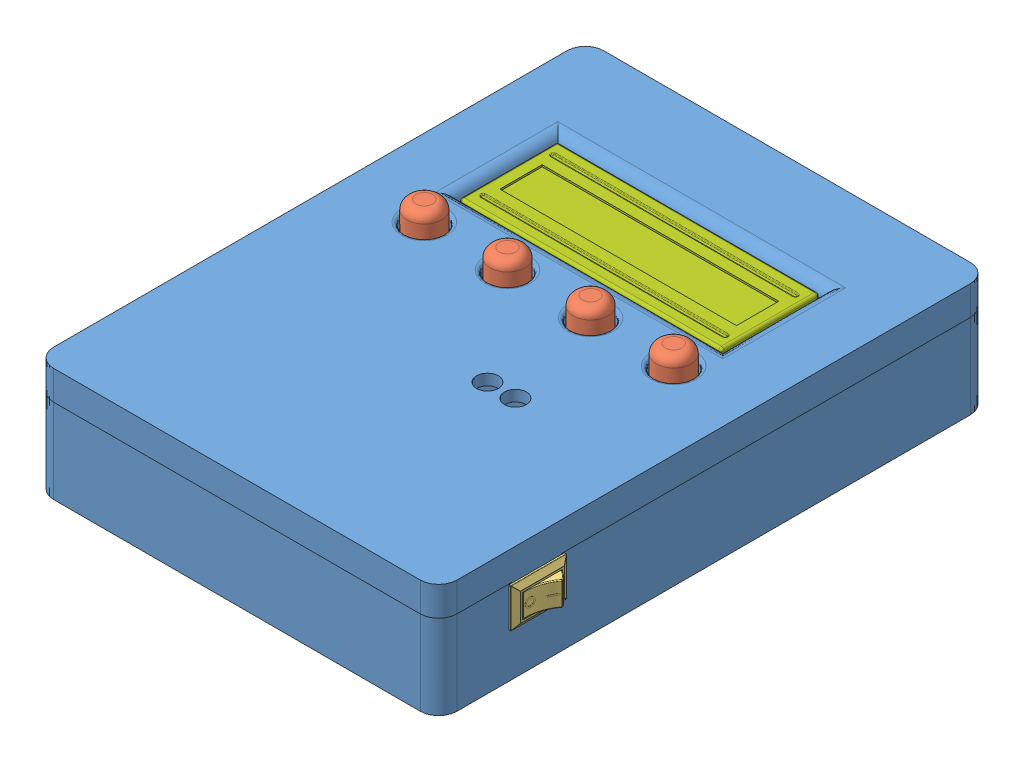
SolidWorks assembly Montagem, configuration Valor predeterminado. Lengths in mm.
Overall size (114.08 36.77 150).
187 component instances, 39 part files, 37 mates.
Components (placement in the parent):
- B01-2: B01 [Valor predeterminado] at (-46.8691 -11.7916 150) size (110 23 150)
- PCB_V02-2: PCB_V02 [Valor predeterminado] at (-92.8691 -3.7916 178) x (1 0 0) z (0 1 0) size (93.53 97.66 25.25)
  - Gerador Senhas.stp-1: Gerador Senhas.stp [Valor predeterminado] at origin size (93.53 97.66 25.7)
    - PCB Component.stp-1: PCB Component.stp [Valor predeterminado] at origin size (93.53 97.66 25.7)
      - ARDUINO-NANO.stp-1: ARDUINO-NANO.stp [Valor predeterminado] at (39.37 21.59 1.57) x (0 -1 0) z (0 0 1) size (17.9 45.1 23.75)
        - PCB.stp-1: PCB.stp [Valor predeterminado] at (-1.2568 4.2028 12.5) x (0 -1 0) z (1 0 0) size (45.1 18 17.9)
          - TopFace.stp-1: TopFace.stp [Valor predeterminado] at origin size (45.1 11.25 12.1)
            - Leds.stp-1: Leds.stp [Valor predeterminado] at origin size (4.2 0.5 12.1)
              - Led.stp-1: Led.stp [Valor predeterminado] at (3.25 0 -13.6) size (4.2 0.5 1.3)
              - Led.stp-2: Led.stp [Valor predeterminado] at (3.25 0 -17.2) size (4.2 0.5 1.3)
              - Led.stp-3: Led.stp [Valor predeterminado] at (3.25 0 -20.8) size (4.2 0.5 1.3)
              - Led (1).stp-1: Led (1).stp [Valor predeterminado] at (3.25 0 -10) size (4.2 0.5 1.3)
            - PinEnd.stp-1: PinEnd.stp [Valor predeterminado] at (0 0 -2.54) size (5.08 11.25 7.62)
              - Pin.stp-1: Pin.stp [Valor predeterminado] at (25 1.6 57.68) x (1 0 0) z (0 0 -1) size (2.54 11.25 2.54)
              - Pin.stp-2: Pin.stp [Valor predeterminado] at (25 1.6 60.22) x (1 0 0) z (0 0 -1) size (2.54 11.25 2.54)
              - Pin.stp-3: Pin.stp [Valor predeterminado] at (25 1.6 62.76) x (1 0 0) z (0 0 -1) size (2.54 11.25 2.54)
              - Pin.stp-4: Pin.stp [Valor predeterminado] at (27.54 1.6 57.68) x (1 0 0) z (0 0 -1) size (2.54 11.25 2.54)
              - Pin.stp-5: Pin.stp [Valor predeterminado] at (27.54 1.6 60.22) x (1 0 0) z (0 0 -1) size (2.54 11.25 2.54)
              - Pin.stp-6: Pin.stp [Valor predeterminado] at (27.54 1.6 62.76) x (1 0 0) z (0 0 -1) size (2.54 11.25 2.54)
            - switch.stp-1: switch.stp [Valor predeterminado] at (1.3966 -1.5 22.3391) size (3 1.7 4.8)
            - chip1.stp-1: chip1.stp [Valor predeterminado] at origin size (11.76 1.3 11.76)
            - USB.stp-1: USB.stp [Valor predeterminado] at origin size (10.18 3.8 11.01)
            - Crystal.stp-1: Crystal.stp [Valor predeterminado] at origin size (2.71 1.1 2.71)
          - BottomFace.stp-1: BottomFace.stp [Valor predeterminado] at origin size (40.75 11.25 17.9)
            - PinRow2.stp-1: PinRow2.stp [Valor predeterminado] at (0 0 17.9) size (38.1 11.25 2.54)
              - Pin (1).stp-1: Pin (1).stp [Valor predeterminado] at (45.58 0 32.1) size (2.54 11.25 2.54)
              - Pin (1).stp-2: Pin (1).stp [Valor predeterminado] at (48.12 0 32.1) size (2.54 11.25 2.54)
              - Pin (1).stp-3: Pin (1).stp [Valor predeterminado] at (50.66 0 32.1) size (2.54 11.25 2.54)
              - Pin (1).stp-4: Pin (1).stp [Valor predeterminado] at (53.2 0 32.1) size (2.54 11.25 2.54)
              - Pin (1).stp-5: Pin (1).stp [Valor predeterminado] at (55.74 0 32.1) size (2.54 11.25 2.54)
              - Pin (1).stp-6: Pin (1).stp [Valor predeterminado] at (58.28 0 32.1) size (2.54 11.25 2.54)
              - Pin (1).stp-7: Pin (1).stp [Valor predeterminado] at (60.82 0 32.1) size (2.54 11.25 2.54)
              - Pin (1).stp-8: Pin (1).stp [Valor predeterminado] at (63.36 0 32.1) size (2.54 11.25 2.54)
              - Pin (1).stp-9: Pin (1).stp [Valor predeterminado] at (43.04 0 32.1) size (2.54 11.25 2.54)
              - Pin (1).stp-10: Pin (1).stp [Valor predeterminado] at (40.5 0 32.1) size (2.54 11.25 2.54)
              - Pin (1).stp-11: Pin (1).stp [Valor predeterminado] at (37.96 0 32.1) size (2.54 11.25 2.54)
              - Pin (1).stp-12: Pin (1).stp [Valor predeterminado] at (35.42 0 32.1) size (2.54 11.25 2.54)
              - Pin (1).stp-13: Pin (1).stp [Valor predeterminado] at (32.88 0 32.1) size (2.54 11.25 2.54)
              - Pin (1).stp-14: Pin (1).stp [Valor predeterminado] at (30.34 0 32.1) size (2.54 11.25 2.54)
              - Pin (1).stp-15: Pin (1).stp [Valor predeterminado] at (27.8 0 32.1) size (2.54 11.25 2.54)
            - PinRow1.stp-1: PinRow1.stp [Valor predeterminado] at origin size (38.1 11.25 2.54)
              - Pin.stp-1: Pin.stp [Valor predeterminado] at (45.58 0 -32.1) size (2.54 11.25 2.54)
              - Pin.stp-2: Pin.stp [Valor predeterminado] at (48.12 0 -32.1) size (2.54 11.25 2.54)
              - Pin.stp-3: Pin.stp [Valor predeterminado] at (50.66 0 -32.1) size (2.54 11.25 2.54)
              - Pin.stp-4: Pin.stp [Valor predeterminado] at (53.2 0 -32.1) size (2.54 11.25 2.54)
              - Pin.stp-5: Pin.stp [Valor predeterminado] at (55.74 0 -32.1) size (2.54 11.25 2.54)
              - Pin.stp-6: Pin.stp [Valor predeterminado] at (58.28 0 -32.1) size (2.54 11.25 2.54)
              - Pin.stp-7: Pin.stp [Valor predeterminado] at (60.82 0 -32.1) size (2.54 11.25 2.54)
              - Pin.stp-8: Pin.stp [Valor predeterminado] at (63.36 0 -32.1) size (2.54 11.25 2.54)
              - Pin.stp-9: Pin.stp [Valor predeterminado] at (43.04 0 -32.1) size (2.54 11.25 2.54)
              - Pin.stp-10: Pin.stp [Valor predeterminado] at (40.5 0 -32.1) size (2.54 11.25 2.54)
              - Pin.stp-11: Pin.stp [Valor predeterminado] at (37.96 0 -32.1) size (2.54 11.25 2.54)
              - Pin.stp-12: Pin.stp [Valor predeterminado] at (35.42 0 -32.1) size (2.54 11.25 2.54)
              - Pin.stp-13: Pin.stp [Valor predeterminado] at (32.88 0 -32.1) size (2.54 11.25 2.54)
              - Pin.stp-14: Pin.stp [Valor predeterminado] at (30.34 0 -32.1) size (2.54 11.25 2.54)
              - Pin.stp-15: Pin.stp [Valor predeterminado] at (27.8 0 -32.1) size (2.54 11.25 2.54)
            - Resistors.stp-1: Resistors.stp [Valor predeterminado] at origin size (32.5 1 11.3)
              - Res.stp-1: Res.stp [Valor predeterminado] at (12.2 1.6 29.15) x (0 0 -1) z (1 0 0) size (1.3 1 4)
              - Res.stp-2: Res.stp [Valor predeterminado] at (12.2 1.6 24.6) x (0 0 -1) z (1 0 0) size (1.3 1 4)
              - Res.stp-3: Res.stp [Valor predeterminado] at (-2.9 1.6 23.1) x (0 0 -1) z (1 0 0) size (1.3 1 4)
              - Res.stp-4: Res.stp [Valor predeterminado] at (-2.9 1.6 26.2) x (0 0 -1) z (1 0 0) size (1.3 1 4)
              - Res.stp-5: Res.stp [Valor predeterminado] at (-16.3 1.6 19.15) x (0 0 -1) z (1 0 0) size (1.3 1 4)
            - caps.stp-1: caps.stp [Valor predeterminado] at origin size (33.2 1.51 4.35)
              - cap.stp-1: cap.stp [Valor predeterminado] at (68.25 1.6 43.825) x (-1 0 0) z (0 0 -1) size (3.7 1.51 1.65)
              - cap.stp-2: cap.stp [Valor predeterminado] at (-14.35 1.6 -32.125) size (3.7 1.51 1.65)
            - respacks.stp-1: respacks.stp [Valor predeterminado] at origin size (3.22 0.9 8.4)
              - respack.stp-1: respack.stp [Valor predeterminado] at (-0.85 1.6 -21.8) size (3.22 0.9 3.4)
              - respack.stp-2: respack.stp [Valor predeterminado] at (-0.85 1.6 -26.8) size (3.22 0.9 3.4)
            - Chip.stp-1: Chip.stp [Valor predeterminado] at origin size (10 1.5 8.03)
            - diode.stp-1: diode.stp [Valor predeterminado] at (0.15 1.6 -28.35) size (1.6 1 4.3)
            - vreg.stp-1: vreg.stp [Valor predeterminado] at (-16.3 1.6 -15.5) size (8.5 1.6 6)
          - PCB-0.stp-1: PCB-0.stp [Valor predeterminado] at origin size (43.7 1.6 17.9)
        - Headers.stp-1: Headers.stp [Valor predeterminado] at (-1.2568 4.2028 12.5) x (0 -1 0) z (1 0 0) size (38.1 11.45 17.78)
          - Header Female 15 v1.stp-1: Header Female 15 v1.stp [Valor predeterminado] at (4.07 12.55 16.51) x (1 0 0) z (0 -1 0) size (38.1 2.54 11.45)
            - HF1.stp-1: HF1.stp [Valor predeterminado] at origin size (2.54 2.54 11.45)
            - HF1.stp-2: HF1.stp [Valor predeterminado] at (2.54 0 0) size (2.54 2.54 11.45)
            - HF1.stp-3: HF1.stp [Valor predeterminado] at (5.08 0 0) size (2.54 2.54 11.45)
            - HF1.stp-4: HF1.stp [Valor predeterminado] at (7.62 0 0) size (2.54 2.54 11.45)
            - HF1.stp-5: HF1.stp [Valor predeterminado] at (10.16 0 0) size (2.54 2.54 11.45)
            - HF1.stp-6: HF1.stp [Valor predeterminado] at (12.7 0 0) size (2.54 2.54 11.45)
            - HF1.stp-7: HF1.stp [Valor predeterminado] at (15.24 0 0) size (2.54 2.54 11.45)
            - HF1.stp-8: HF1.stp [Valor predeterminado] at (17.78 0 0) size (2.54 2.54 11.45)
            - HF1.stp-9: HF1.stp [Valor predeterminado] at (20.32 0 0) size (2.54 2.54 11.45)
            - HF1.stp-10: HF1.stp [Valor predeterminado] at (22.86 0 0) size (2.54 2.54 11.45)
            - HF1.stp-11: HF1.stp [Valor predeterminado] at (25.4 0 0) size (2.54 2.54 11.45)
            - HF1.stp-12: HF1.stp [Valor predeterminado] at (27.94 0 0) size (2.54 2.54 11.45)
            - HF1.stp-13: HF1.stp [Valor predeterminado] at (30.48 0 0) size (2.54 2.54 11.45)
            - HF1.stp-14: HF1.stp [Valor predeterminado] at (33.02 0 0) size (2.54 2.54 11.45)
            - HF1.stp-15: HF1.stp [Valor predeterminado] at (35.56 0 0) size (2.54 2.54 11.45)
          - Header Female 15 v1 (1).stp-1: Header Female 15 v1 (1).stp [Valor predeterminado] at (4.07 12.55 1.27) x (1 0 0) z (0 -1 0) size (38.1 2.54 11.45)
            - HF1.stp-1: HF1.stp [Valor predeterminado] at origin size (2.54 2.54 11.45)
            - HF1.stp-2: HF1.stp [Valor predeterminado] at (2.54 0 0) size (2.54 2.54 11.45)
            - HF1.stp-3: HF1.stp [Valor predeterminado] at (5.08 0 0) size (2.54 2.54 11.45)
            - HF1.stp-4: HF1.stp [Valor predeterminado] at (7.62 0 0) size (2.54 2.54 11.45)
            - HF1.stp-5: HF1.stp [Valor predeterminado] at (10.16 0 0) size (2.54 2.54 11.45)
            - HF1.stp-6: HF1.stp [Valor predeterminado] at (12.7 0 0) size (2.54 2.54 11.45)
            - HF1.stp-7: HF1.stp [Valor predeterminado] at (15.24 0 0) size (2.54 2.54 11.45)
            - HF1.stp-8: HF1.stp [Valor predeterminado] at (17.78 0 0) size (2.54 2.54 11.45)
            - HF1.stp-9: HF1.stp [Valor predeterminado] at (20.32 0 0) size (2.54 2.54 11.45)
            - HF1.stp-10: HF1.stp [Valor predeterminado] at (22.86 0 0) size (2.54 2.54 11.45)
            - HF1.stp-11: HF1.stp [Valor predeterminado] at (25.4 0 0) size (2.54 2.54 11.45)
            - HF1.stp-12: HF1.stp [Valor predeterminado] at (27.94 0 0) size (2.54 2.54 11.45)
            - HF1.stp-13: HF1.stp [Valor predeterminado] at (30.48 0 0) size (2.54 2.54 11.45)
            - HF1.stp-14: HF1.stp [Valor predeterminado] at (33.02 0 0) size (2.54 2.54 11.45)
            - HF1.stp-15: HF1.stp [Valor predeterminado] at (35.56 0 0) size (2.54 2.54 11.45)
      - PUSHBUTTON.stp-1: PUSHBUTTON.stp [Valor predeterminado] at (12 38.1 1.57) size (7.7 6 7.8)
        - B3F_1000_BUTTON.stp-1: B3F_1000_BUTTON.stp [Valor predeterminado] at (0 0 4.3) x (-1 0 0) z (0 1 0) size (3.5 1 3.5)
        - B3F_1000_BASE.stp-1: B3F_1000_BASE.stp [Valor predeterminado] x (1 0 0) z (0 -1 0) size (7.7 7.4 6)
      - PUSHBUTTON.stp-2: PUSHBUTTON.stp [Valor predeterminado] at (34.667 38.1 1.57) size (7.7 6 7.8)
        - B3F_1000_BUTTON.stp-1: B3F_1000_BUTTON.stp [Valor predeterminado] at (0 0 4.3) x (-1 0 0) z (0 1 0) size (3.5 1 3.5)
        - B3F_1000_BASE.stp-1: B3F_1000_BASE.stp [Valor predeterminado] x (1 0 0) z (0 -1 0) size (7.7 7.4 6)
      - PUSHBUTTON.stp-3: PUSHBUTTON.stp [Valor predeterminado] at (57.333 38.1 1.57) size (7.7 6 7.8)
        - B3F_1000_BUTTON.stp-1: B3F_1000_BUTTON.stp [Valor predeterminado] at (0 0 4.3) x (-1 0 0) z (0 1 0) size (3.5 1 3.5)
        - B3F_1000_BASE.stp-1: B3F_1000_BASE.stp [Valor predeterminado] x (1 0 0) z (0 -1 0) size (7.7 7.4 6)
      - PUSHBUTTON.stp-4: PUSHBUTTON.stp [Valor predeterminado] at (80 38.1 1.57) size (7.7 6 7.8)
        - B3F_1000_BUTTON.stp-1: B3F_1000_BUTTON.stp [Valor predeterminado] at (0 0 4.3) x (-1 0 0) z (0 1 0) size (3.5 1 3.5)
        - B3F_1000_BASE.stp-1: B3F_1000_BASE.stp [Valor predeterminado] x (1 0 0) z (0 -1 0) size (7.7 7.4 6)
      - 1N4004.stp-1: 1N4004.stp [Valor predeterminado] at (73.66 2.54 1.57) size (10.38 2.7 5.35)
        - User Library-DO-41_375mil_Fillet001.stp-1: User Library-DO-41_375mil_Fillet001.stp [Valor predeterminado] at (4.7457 0.3612 0) x (-1 0 0) z (0 0 1) size (3.72 2.7 2.7)
        - User Library-DO-41_375mil_Fillet.stp-1: User Library-DO-41_375mil_Fillet.stp [Valor predeterminado] at (4.7457 0.3612 0) x (-1 0 0) z (0 0 1) size (1 2.7 2.7)
        - User Library-DO-41_375mil_DO_41_375mil001.stp-1: User Library-DO-41_375mil_DO_41_375mil001.stp [Valor predeterminado] at (4.7457 0.3612 0) x (-1 0 0) z (0 0 1) size (2.55 0.86 4.43)
        - User Library-DO-41_375mil_DO_41_375mil.stp-1: User Library-DO-41_375mil_DO_41_375mil.stp [Valor predeterminado] at (4.7457 0.3612 0) x (-1 0 0) z (0 0 1) size (2.55 0.86 4.43)
        - User Library-DO-41_375mil_DO_41_375mil003.stp-1: User Library-DO-41_375mil_DO_41_375mil003.stp [Valor predeterminado] at (4.7457 0.3612 0) x (-1 0 0) z (0 0 1) size (1 2.7 2.7)
      - LCD-16X2-V2.stp-1: LCD-16X2-V2.stp [Valor predeterminado] at (46 64.77 1.57) size (80.7 36 23.25)
        - DISPLAY-LCD.stp-1: DISPLAY-LCD.stp [Valor predeterminado] at (-0.3985 0.0488 8.5541) size (80.7 36 16.8)
        - Header Female 15 v1 (2).stp-1: Header Female 15 v1 (2).stp [Valor predeterminado] at (-29.5885 15.5718 0.0005) size (38.1 2.54 11.45)
        - Header Female 15 v1 - Copia.stp-1: Header Female 15 v1 - Copia.stp [Valor predeterminado] at (-32.1285 15.5718 0.0005) size (2.54 2.54 11.45)
      - Board.stp-1: Board.stp [Valor predeterminado] at origin size (92 94 1.57)
      - 10k.stp-1: 10k.stp [Valor predeterminado] at (57.15 21.59 1.57) x (0 1 0) z (0 0 1) size (8.2 1.6 3.52)
      - 10k.stp-2: 10k.stp [Valor predeterminado] at (64.77 21.59 1.57) x (0 1 0) z (0 0 1) size (8.2 1.6 3.52)
      - 10k.stp-3: 10k.stp [Valor predeterminado] at (15.24 43.18 1.57) size (8.2 1.6 3.52)
      - 10k.stp-4: 10k.stp [Valor predeterminado] at (38.1 43.18 1.57) size (8.2 1.6 3.52)
      - 10k.stp-5: 10k.stp [Valor predeterminado] at (60.96 43.18 1.57) size (8.2 1.6 3.52)
      - 10k.stp-6: 10k.stp [Valor predeterminado] at (83.82 43.18 1.57) size (8.2 1.6 3.52)
      - 1X02_90.stp-1: 1X02_90.stp [Valor predeterminado] at (83.82 2.54 1.57) x (-1 0 0) z (0 0 1) size (5.08 10.36 5.54)
      - LED5MM.stp-1: LED5MM.stp [Valor predeterminado] at (58.42 8.89 1.57) size (5.1 5.1 13.6)
      - LED5MM.stp-2: LED5MM.stp [Valor predeterminado] at (66.04 8.89 1.57) size (5.1 5.1 13.6)
  - pan head cross recess screw_iso-1: pan head cross recess screw_iso [ISO 7045 - M2 x 20 - Z - 20N] at (83.5 80.27 -1.6) x (0 0 1) z (-1 0 0) size (21.57 4 4)
  - pan head cross recess screw_iso-2: pan head cross recess screw_iso [ISO 7045 - M2 x 20 - Z - 20N] at (83.5 49.27 -1.6) x (0 0 1) z (-1 0 0) size (21.57 4 4)
  - pan head cross recess screw_iso-3: pan head cross recess screw_iso [ISO 7045 - M2 x 20 - Z - 20N] at (8.5 49.27 -1.6) x (0 0 1) z (-1 0 0) size (21.57 4 4)
  - pan head cross recess screw_iso-4: pan head cross recess screw_iso [ISO 7045 - M2 x 20 - Z - 20N] at (8.5 80.27 -1.6) x (0 0 1) z (-1 0 0) size (21.57 4 4)
  - plain washer 10673 type snl_iso-1: plain washer 10673 type snl_iso [ISO 10673-2.25-S] at (83.5 80.27 1.57) x (0 0 1) z (-1 0 0) size (0.6 5 5)
  - plain washer 10673 type snl_iso-2: plain washer 10673 type snl_iso [ISO 10673-2.25-S] at (83.6015 80.6118 14.0205) x (0 0 1) z (-1 0 0) size (0.6 5 5)
  - plain washer 10673 type snl_iso-3: plain washer 10673 type snl_iso [ISO 10673-2.25-S] at (83.6015 80.6118 12.5205) x (0 0 -1) z (1 0 0) size (0.6 5 5)
  - plain washer 10673 type snl_iso-4: plain washer 10673 type snl_iso [ISO 10673-2.25-S] at (83.5 49.27 12.2061) x (0 0 1) z (-1 0 0) size (0.6 5 5)
  - plain washer 10673 type snl_iso-5: plain washer 10673 type snl_iso [ISO 10673-2.25-S] at (83.6015 48.6118 14.0205) x (0 0 1) z (-1 0 0) size (0.6 5 5)
  - plain washer 10673 type snl_iso-6: plain washer 10673 type snl_iso [ISO 10673-2.25-S] at (83.5 49.27 1.57) x (0 0 1) z (-1 0 0) size (0.6 5 5)
  - plain washer 10673 type snl_iso-7: plain washer 10673 type snl_iso [ISO 10673-2.25-S] at (8.5 49.27 1.763) x (0 0 1) z (-1 0 0) size (0.6 5 5)
  - plain washer 10673 type snl_iso-8: plain washer 10673 type snl_iso [ISO 10673-2.25-S] at (7.6015 48.6118 14.0205) x (0 0 1) z (-1 0 0) size (0.6 5 5)
  - plain washer 10673 type snl_iso-9: plain washer 10673 type snl_iso [ISO 10673-2.25-S] at (7.6015 80.6118 14.0205) x (0 0 1) z (-1 0 0) size (0.6 5 5)
  - plain washer 10673 type snl_iso-10: plain washer 10673 type snl_iso [ISO 10673-2.25-S] at (8.5 80.27 1.57) x (0 0 1) z (-1 0 0) size (0.6 5 5)
  - plain washer 10673 type snl_iso-12: plain washer 10673 type snl_iso [ISO 10673-2.25-S] at (7.6015 48.6118 12.5205) x (0 0 -1) z (1 0 0) size (0.6 5 5)
  - plain washer 10673 type snl_iso-13: plain washer 10673 type snl_iso [ISO 10673-2.25-S] at (7.6015 80.6118 12.5205) x (0 0 -1) z (1 0 0) size (0.6 5 5)
  - hex thin nut gradeb_iso-2: hex thin nut gradeb_iso [ISO - 4036 - M1.6 - N] at (83.6015 80.6118 15.6205) size (3.2 3.7 1)
  - hex thin nut gradeb_iso-3: hex thin nut gradeb_iso [ISO - 4036 - M1.6 - N] at (83.5 80.27 3.17) size (3.2 3.7 1)
  - hex thin nut gradeb_iso-4: hex thin nut gradeb_iso [ISO - 4036 - M1.6 - N] at (83.6015 80.6118 10.9205) x (0.923728 0.383049 0) z (0 0 -1) size (3.2 3.7 1)
  - hex thin nut gradeb_iso-5: hex thin nut gradeb_iso [ISO - 4036 - M1.6 - N] at (83.5 49.27 11.2061) x (0.923728 0.383049 0) z (0 0 -1) size (3.2 3.7 1)
  - hex thin nut gradeb_iso-6: hex thin nut gradeb_iso [ISO - 4036 - M1.6 - N] at (83.5 49.27 3.17) size (3.2 3.7 1)
  - hex thin nut gradeb_iso-7: hex thin nut gradeb_iso [ISO - 4036 - M1.6 - N] at (83.6015 48.6118 15.6205) size (3.2 3.7 1)
  - hex thin nut gradeb_iso-8: hex thin nut gradeb_iso [ISO - 4036 - M1.6 - N] at (7.6015 80.6118 15.6205) size (3.2 3.7 1)
  - hex thin nut gradeb_iso-9: hex thin nut gradeb_iso [ISO - 4036 - M1.6 - N] at (7.6015 48.6118 15.6205) size (3.2 3.7 1)
  - hex thin nut gradeb_iso-10: hex thin nut gradeb_iso [ISO - 4036 - M1.6 - N] at (7.6015 48.6118 10.9205) x (0.923728 0.383049 0) z (0 0 -1) size (3.2 3.7 1)
  - hex thin nut gradeb_iso-11: hex thin nut gradeb_iso [ISO - 4036 - M1.6 - N] at (8.5 80.27 10.9205) x (-0.825808 -0.563951 0) z (0 0 -1) size (3.2 3.7 1)
  - hex thin nut gradeb_iso-12: hex thin nut gradeb_iso [ISO - 4036 - M1.6 - N] at (8.5 80.27 3.17) size (3.2 3.7 1)
  - hex thin nut gradeb_iso-13: hex thin nut gradeb_iso [ISO - 4036 - M1.6 - N] at (8.5 49.27 3.363) size (3.2 3.7 1)
- countersunk flat head cross recess screw_iso-1: countersunk flat head cross recess screw_iso [ISO 7046-1 - M3 x 16 - Z - 16N] at (-8.8691 -11.7916 90) x (0 1 0) z (0.016803 0 0.999859) size (16 5.5 5.5)
- countersunk flat head cross recess screw_iso-2: countersunk flat head cross recess screw_iso [ISO 7046-1 - M3 x 16 - Z - 16N] at (-8.8691 -11.7916 163) x (0 1 0) z (0.01222 0 0.999925) size (16 5.5 5.5)
- countersunk flat head cross recess screw_iso-3: countersunk flat head cross recess screw_iso [ISO 7046-1 - M3 x 16 - Z - 16N] at (-84.8691 -11.7916 148) x (0 1 0) z (0 0 1) size (16 5.5 5.5)
- countersunk flat head cross recess screw_iso-4: countersunk flat head cross recess screw_iso [ISO 7046-1 - M3 x 16 - Z - 16N] at (-84.8691 -11.7916 92) x (0 1 0) z (0.018147 0 0.999835) size (16 5.5 5.5)
- plain washer 10673 type snl_iso-1: plain washer 10673 type snl_iso [ISO 10673-3.2-S] at (-8.8691 0.079 90) x (0 1 0) z (0 0 1) size (0.8 7 7)
- plain washer 10673 type snl_iso-2: plain washer 10673 type snl_iso [ISO 10673-3.2-S] at (-8.8691 0.0706 163) x (0 1 0) z (0 0 1) size (0.8 7 7)
- plain washer 10673 type snl_iso-3: plain washer 10673 type snl_iso [ISO 10673-3.2-S] at (-84.8691 -2.2216 148) x (0 1 0) z (0 0 1) size (0.8 7 7)
- plain washer 10673 type snl_iso-4: plain washer 10673 type snl_iso [ISO 10673-3.2-S] at (-84.8691 -2.2216 92) x (0 1 0) z (0 0 1) size (0.8 7 7)
- hex thin nut chamfered gradeab_iso-1: hex thin nut chamfered gradeab_iso [ISO - 4035 - M3 - N] at (-8.8691 2.679 90) x (1 0 0) z (0 1 0) size (5.5 6.35 1.8)
- hex thin nut chamfered gradeab_iso-2: hex thin nut chamfered gradeab_iso [ISO - 4035 - M3 - N] at (-8.8691 2.6706 163) x (1 0 0) z (0 1 0) size (5.5 6.35 1.8)
- hex thin nut chamfered gradeab_iso-3: hex thin nut chamfered gradeab_iso [ISO - 4035 - M3 - N] at (-84.8691 0.3784 148) x (1 0 0) z (0 1 0) size (5.5 6.35 1.8)
- hex thin nut chamfered gradeab_iso-4: hex thin nut chamfered gradeab_iso [ISO - 4035 - M3 - N] at (-84.8691 0.3784 92) x (1 0 0) z (0 1 0) size (5.5 6.35 1.8)
- B02-1: B02 [Valor predeterminado] at (-46.8691 19.2084 150) size (110 9 150)
- BT-1: BT [Valor predeterminado] at (-6.001 2.0784 140.016) x (0.999857 0 0.016893) z (-0.016893 0 0.999857) size (13.5 22.5 13.5)
- BT-2: BT [Valor predeterminado] at (-28.6667 2.0784 139.9) size (13.5 22.5 13.5)
- BT-3: BT [Valor predeterminado] at (-51.3334 2.0784 139.9) size (13.5 22.5 13.5)
- BT-4: BT [Valor predeterminado] at (-74 2.0784 139.9) size (13.5 22.5 13.5)
- countersunk flat head cross recess screw_iso-5: countersunk flat head cross recess screw_iso [ISO 7046-1 - M3 x 25 - Z - 25N] at (-96.8691 -11.7916 80) x (0 1 0) z (0.026158 0 0.999658) size (25 5.5 5.5)
- countersunk flat head cross recess screw_iso-6: countersunk flat head cross recess screw_iso [ISO 7046-1 - M3 x 25 - Z - 25N] at (3.1309 -11.7916 80) x (0 1 0) z (-0.021009 0 0.999779) size (25 5.5 5.5)
- countersunk flat head cross recess screw_iso-7: countersunk flat head cross recess screw_iso [ISO 7046-1 - M3 x 25 - Z - 25N] at (3.1309 -11.7916 220) x (0 1 0) z (0.093067 0 0.99566) size (25 5.5 5.5)
- countersunk flat head cross recess screw_iso-8: countersunk flat head cross recess screw_iso [ISO 7046-1 - M3 x 25 - Z - 25N] at (-96.8691 -12.1916 220) x (0 1 0) z (0 0 1) size (25 5.5 5.5)
- Mini Rocker Switch-1: Mini Rocker Switch [Default] at (8.1309 5.6534 198.25) x (0 -1 0) z (0 0 1) size (10.67 19.51 15.75)
Mates (geometry in assembly coordinates):
- Concêntrico2: concentric anti-aligned: cylinder of B01-2 through (-84.8691 -11.7916 92) axis (0 -1 0) radius 1.7; cylinder of PCB_V02-2/Gerador Senhas.stp-1/PCB Component.stp-1/Board.stp-1 through (-84.8691 -3.7916 92) axis (0 1 0) radius 1.75
- Concêntrico3: concentric anti-aligned: cylinder of B01-2 through (-8.8691 -11.7916 163) axis (0 -1 0) radius 1.7; cylinder of PCB_V02-2/Gerador Senhas.stp-1/PCB Component.stp-1/Board.stp-1 through (-8.8691 -3.7916 163) axis (0 1 0) radius 1.75
- Coincidente1: coincident anti-aligned: circle of B01-2; plane of PCB_V02-2/Gerador Senhas.stp-1/PCB Component.stp-1/Board.stp-1 through (-46.8691 -3.7916 131) normal (0 -1 0)
- Coincidente2: coincident aligned: cone of B01-2 through (-8.8691 -11.7916 90) axis (0 1 0); cone of countersunk flat head cross recess screw_iso-1 through (-8.8691 -11.3916 90) axis (0 1 0)
- Coincidente3: coincident aligned: cone of B01-2 through (-8.8691 -11.7916 163) axis (0 1 0); cone of countersunk flat head cross recess screw_iso-2 through (-8.8691 -11.3916 163) axis (0 1 0)
- Coincidente5: coincident aligned: cone of B01-2 through (-84.8691 -11.7916 92) axis (0 1 0); cone of countersunk flat head cross recess screw_iso-4 through (-84.8691 -11.3916 92) axis (0 1 0)
- Concêntrico4: concentric aligned: cylinder of countersunk flat head cross recess screw_iso-1 through (-8.8691 -18.1416 90) axis (0 -1 0) radius 1.5; cylinder of plain washer 10673 type snl_iso-1 through (-8.8691 0.879 90) axis (0 -1 0) radius 1.6
- Concêntrico5: concentric aligned: cylinder of countersunk flat head cross recess screw_iso-2 through (-8.8691 -18.1416 163) axis (0 -1 0) radius 1.5; cylinder of plain washer 10673 type snl_iso-2 through (-8.8691 0.8706 163) axis (0 -1 0) radius 1.6
- Concêntrico6: concentric anti-aligned: cylinder of PCB_V02-2/Gerador Senhas.stp-1/PCB Component.stp-1/Board.stp-1 through (-84.8691 -3.7916 148) axis (0 1 0) radius 1.75; cylinder of plain washer 10673 type snl_iso-3 through (-84.8691 -1.4216 148) axis (0 -1 0) radius 1.6
- Coincidente6: coincident anti-aligned: plane of PCB_V02-2/Gerador Senhas.stp-1/PCB Component.stp-1/Board.stp-1 through (-46.8691 -2.2216 131) normal (0 1 0); plane of plain washer 10673 type snl_iso-3 through (-84.8691 -2.2216 148) normal (0 -1 0)
- Concêntrico7: concentric anti-aligned: cylinder of PCB_V02-2/Gerador Senhas.stp-1/PCB Component.stp-1/Board.stp-1 through (-84.8691 -3.7916 92) axis (0 1 0) radius 1.75; cylinder of plain washer 10673 type snl_iso-4 through (-84.8691 -1.4216 92) axis (0 -1 0) radius 1.6
- Coincidente7: coincident anti-aligned: plane of PCB_V02-2/Gerador Senhas.stp-1/PCB Component.stp-1/Board.stp-1 through (-46.8691 -2.2216 131) normal (0 1 0); plane of plain washer 10673 type snl_iso-4 through (-84.8691 -2.2216 92) normal (0 -1 0)
- Concêntrico9: concentric anti-aligned: cylinder of plain washer 10673 type snl_iso-1 through (-8.8691 0.879 90) axis (0 -1 0) radius 1.6; cylinder of hex thin nut chamfered gradeab_iso-1 through (-8.8691 -22.3585 90) axis (0 1 0) radius 1.5
- Coincidente9: coincident anti-aligned: plane of plain washer 10673 type snl_iso-1 through (-8.8691 0.879 90) normal (0 1 0); plane of hex thin nut chamfered gradeab_iso-1 through (-14.3691 0.879 90) normal (0 -1 0)
- Concêntrico10: concentric anti-aligned: cylinder of plain washer 10673 type snl_iso-2 through (-8.8691 0.8706 163) axis (0 -1 0) radius 1.6; cylinder of hex thin nut chamfered gradeab_iso-2 through (-8.8691 -22.3669 163) axis (0 1 0) radius 1.5
- Coincidente10: coincident anti-aligned: plane of plain washer 10673 type snl_iso-2 through (-8.8691 0.8706 163) normal (0 1 0); plane of hex thin nut chamfered gradeab_iso-2 through (-14.3691 0.8706 163) normal (0 -1 0)
- Concêntrico11: concentric anti-aligned: cylinder of plain washer 10673 type snl_iso-3 through (-84.8691 -1.4216 148) axis (0 -1 0) radius 1.6; cylinder of hex thin nut chamfered gradeab_iso-3 through (-84.8691 -24.6591 148) axis (0 1 0) radius 1.5
- Coincidente11: coincident anti-aligned: plane of plain washer 10673 type snl_iso-3 through (-84.8691 -1.4216 148) normal (0 1 0); plane of hex thin nut chamfered gradeab_iso-3 through (-90.3691 -1.4216 148) normal (0 -1 0)
- Concêntrico12: concentric anti-aligned: cylinder of plain washer 10673 type snl_iso-4 through (-84.8691 -1.4216 92) axis (0 -1 0) radius 1.6; cylinder of hex thin nut chamfered gradeab_iso-4 through (-84.8691 -24.6591 92) axis (0 1 0) radius 1.5
- Coincidente12: coincident anti-aligned: plane of plain washer 10673 type snl_iso-4 through (-84.8691 -1.4216 92) normal (0 1 0); plane of hex thin nut chamfered gradeab_iso-4 through (-90.3691 -1.4216 92) normal (0 -1 0)
- Coincidente13: coincident anti-aligned: circle of B01-2; circle of B02-1
- Coincidente14: coincident anti-aligned: circle of B01-2; circle of B02-1
- Concêntrico13: concentric anti-aligned: cylinder of B02-1 through (-12.8691 14.2084 139.9) axis (0 1 0) radius 5.25; cylinder of BT-1 through (-12.8691 2.0784 139.9) axis (0 -1 0) radius 4.75
- Coincidente15: coincident anti-aligned: plane of PCB_V02-2/Gerador Senhas.stp-1/PCB Component.stp-1/PUSHBUTTON.stp-4/B3F_1000_BUTTON.stp-1 through (-12.8691 2.0784 139.9) normal (0 1 0); circle of BT-1
- Coincidente22: coincident anti-aligned: plane of PCB_V02-2/Gerador Senhas.stp-1/PCB Component.stp-1/PUSHBUTTON.stp-3/B3F_1000_BUTTON.stp-1 through (-35.5361 2.0784 139.9) normal (0 1 0); circle of BT-2
- Coincidente23: coincident anti-aligned: plane of PCB_V02-2/Gerador Senhas.stp-1/PCB Component.stp-1/PUSHBUTTON.stp-2/B3F_1000_BUTTON.stp-1 through (-58.2021 2.0784 139.9) normal (0 1 0); circle of BT-3
- Coincidente24: coincident anti-aligned: plane of PCB_V02-2/Gerador Senhas.stp-1/PCB Component.stp-1/PUSHBUTTON.stp-1/B3F_1000_BUTTON.stp-1 through (-80.8691 2.0784 139.9) normal (0 1 0); circle of BT-4
- Concêntrico14: concentric anti-aligned: cylinder of B02-1 through (-35.5358 14.2084 139.9) axis (0 1 0) radius 5.25; cylinder of BT-2 through (-35.5358 2.0784 139.9) axis (0 -1 0) radius 4.75
- Concêntrico15: concentric anti-aligned: cylinder of B02-1 through (-58.2025 14.2084 139.9) axis (0 1 0) radius 5.25; cylinder of BT-3 through (-58.2025 2.0784 139.9) axis (0 -1 0) radius 4.75
- Concêntrico16: concentric anti-aligned: cylinder of B02-1 through (-80.8691 14.2084 139.9) axis (0 1 0) radius 5.25; cylinder of BT-4 through (-80.8691 2.0784 139.9) axis (0 -1 0) radius 4.75
- Coincidente25: coincident aligned: cone of B01-2 through (-96.8691 -11.7916 80) axis (0 1 0); cone of countersunk flat head cross recess screw_iso-5 through (-96.8691 -11.3916 80) axis (0 1 0)
- Coincidente26: coincident aligned: cone of B01-2 through (3.1309 -11.7916 80) axis (0 1 0); cone of countersunk flat head cross recess screw_iso-6 through (3.1309 -11.3916 80) axis (0 1 0)
- Coincidente27: coincident aligned: cone of B01-2 through (3.1309 -11.7916 220) axis (0 1 0); cone of countersunk flat head cross recess screw_iso-7 through (3.1309 -11.3916 220) axis (0 1 0)
- Concêntrico17: concentric aligned: cone of B01-2 through (-96.8691 -11.7916 220) axis (0 1 0); cone of countersunk flat head cross recess screw_iso-8 through (-96.8691 -11.7916 220) axis (0 1 0)
- Coincidente28: coincident anti-aligned: plane of B01-2 through (-46.8691 1.2084 150) normal (0 1 0); plane of Mini Rocker Switch-1 through (8.1309 1.2084 198.25) normal (0 -1 0)
- Largura1: width aligned: plane of B01-2 through (5.1309 1.2084 191.5) normal (0 0 1); plane of Mini Rocker Switch-1 through (5.1309 1.2084 205) normal (0 0 -1); plane of B01-2 through (8.1309 15.6575 204.3206) normal (0 0 1); plane of Mini Rocker Switch-1 through (8.1309 15.6575 192.1794) normal (0 0 -1)
- Coincidente29: coincident anti-aligned: plane of B01-2 through (8.1309 11.2084 225) normal (1 0 0); plane of Mini Rocker Switch-1 through (8.1309 5.6534 198.25) normal (-1 0 0)
